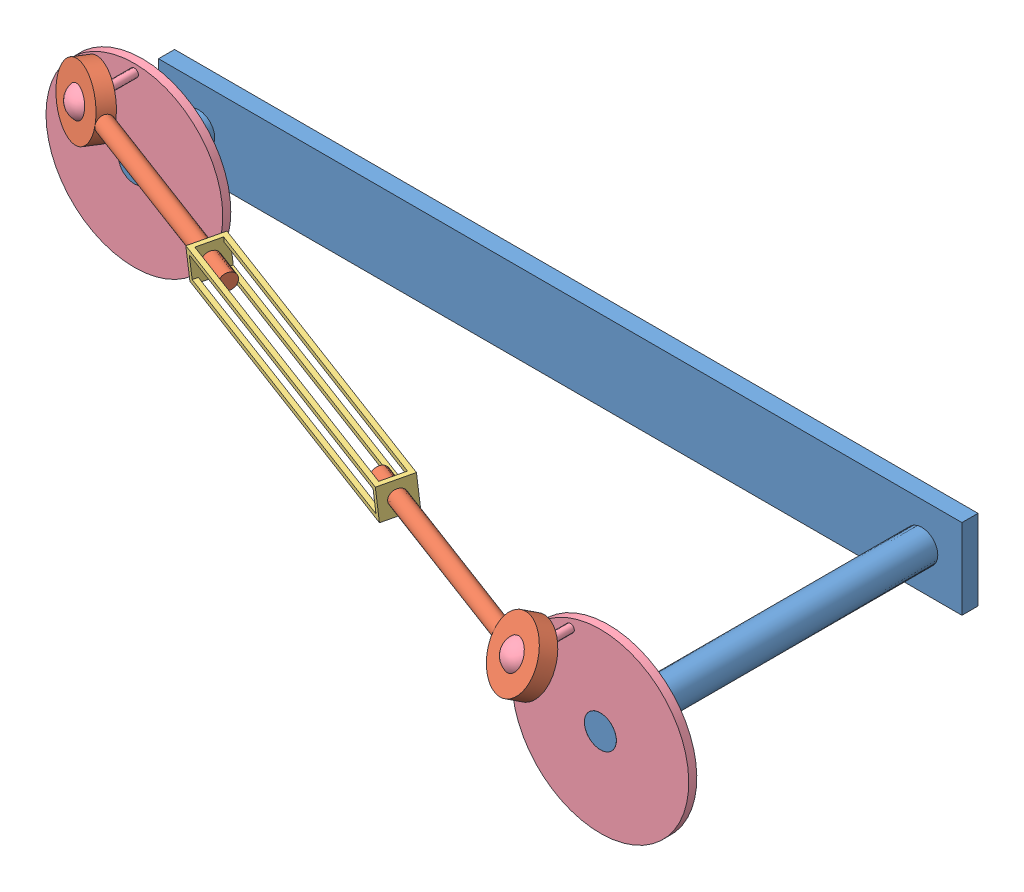
SolidWorks assembly Ensamblaje Pieza 1 Tarea 2, configuration Predeterminado. Lengths in mm.
Overall size (576.6 147.83 259.44).
6 component instances, 4 part files, 11 mates.
Components (placement in the parent):
- T02 EJER01 Base-1: T02 EJER01 Base [Default] at origin size (500 50 210)
- T02 EJER01 Connecting_Rod-1: T02 EJER01 Connecting_Rod [Default] at (456.2697 71.3592 240) x (-0.937528 0.007915 -0.347821) z (-0.308309 0.444334 0.841138) size (170 40 10)
- T02 EJER01 Connector_Block-1: T02 EJER01 Connector_Block [Default] at (142.7645 63.0036 133.2025) x (0.937528 -0.007915 0.347821) z (-0.028404 0.994663 0.099194) size (200 20 20)
- T02 EJER01 Wheel_component-1: T02 EJER01 Wheel_component [Default] at (456.2697 71.3592 240) x (0 0 -1) z (0.927184 0.374607 0) size (45 115 110)
- T02 EJER01 Connecting_Rod-2: T02 EJER01 Connecting_Rod [Default] at (25 75 80) x (0.937528 -0.007915 0.347821) z (0.342618 -0.152716 -0.926979) size (170 40 10)
- T02 EJER01 Wheel_component-2: T02 EJER01 Wheel_component [Default] at (25 75 80) x (0 0 -1) z (1 0 0) size (45 115 110)
Mates (geometry in assembly coordinates):
- Concéntrica2: concentric anti-aligned: cylinder of T02 EJER01 Base-1 through (475 25 210) axis (0 0 -1) radius 10; cylinder of T02 EJER01 Wheel_component-1 through (475 25 205) axis (0 0 1) radius 10
- Coincidente5: coincident aligned: plane of T02 EJER01 Base-1 through (250 -365.9899 210) normal (0 0 1); plane of T02 EJER01 Wheel_component-1 through (475 25 210) normal (0 0 1)
- Concéntrica3: concentric anti-aligned: cylinder of T02 EJER01 Base-1 through (25 25 50) axis (0 0 -1) radius 10; cylinder of T02 EJER01 Wheel_component-2 through (25 25 45) axis (0 0 1) radius 10
- Coincidente6: coincident aligned: plane of T02 EJER01 Base-1 through (250 -365.9899 50) normal (0 0 1); plane of T02 EJER01 Wheel_component-2 through (25 25 50) normal (0 0 1)
- Concéntrica4: concentric: sphere of T02 EJER01 Connecting_Rod-1; sphere of T02 EJER01 Wheel_component-1
- Concéntrica5: concentric: sphere of T02 EJER01 Connecting_Rod-2; sphere of T02 EJER01 Wheel_component-2
- Ángulo1: planar angle = 0.383972 rad aligned: line of T02 EJER01 Base-1 through (500 0 10) axis (0 1 0); line of T02 EJER01 Wheel_component-1 through (475 25 210) axis (-0.374607 0.927184 0)
- Concéntrica8: concentric aligned: circle of T02 EJER01 Connecting_Rod-1; circle of T02 EJER01 Connector_Block-1
- Distancia2: distance = 16 mm aligned: plane of T02 EJER01 Connector_Block-1 through (326.8894 81.3376 203.707) normal (-0.937528 0.007915 -0.347821); plane of T02 EJER01 Connecting_Rod-1 through (315.6405 72.5464 187.8269) normal (-0.937528 0.007915 -0.347821)
- Concéntrica9: concentric anti-aligned: circle of T02 EJER01 Connector_Block-1; circle of T02 EJER01 Connecting_Rod-2
- Paralelo2: parallel anti-aligned: line of T02 EJER01 Base-1 through (0 50 10) axis (0 -1 0); line of T02 EJER01 Wheel_component-2 through (25 25 50) axis (0 1 0)
